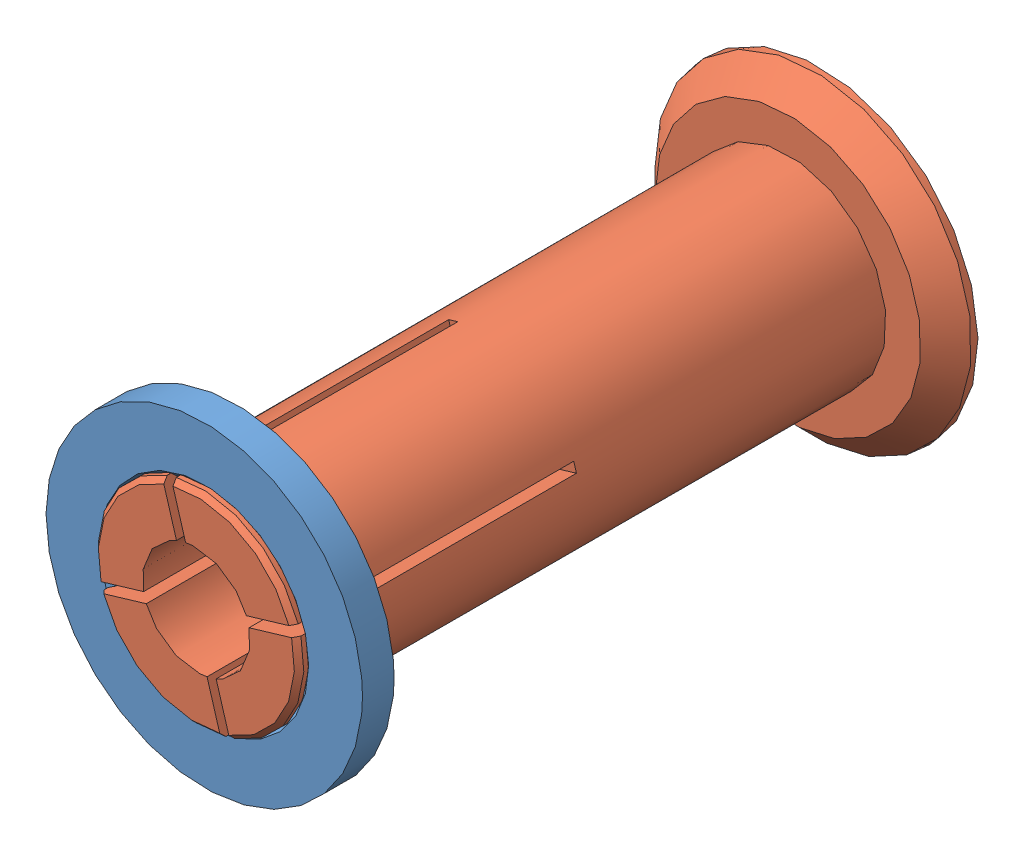
SolidWorks assembly 32-92-17-spool-adapter, configuration Default. Lengths in mm.
Overall size (62.18 62.18 98.5).
2 component instances, 2 part files, 2 mates.
Components (placement in the parent):
- 32-92-17-spool-adapter-female-1: 32-92-17-spool-adapter-female [Default] at (21.1752 30.9981 31.2213) size (50 50 5)
- 32-92-17-spool-adapter-male-1: 32-92-17-spool-adapter-male [Default] at (21.1752 30.9981 -56.0287) x (0.95852 0.285025 0) z (0 0 1) size (50 50 98.5)
Mates (geometry in assembly coordinates):
- Concentric1: concentric anti-aligned: cylinder of 32-92-17-spool-adapter-female-1 through (21.1752 30.9981 31.2213) axis (0 0 1) radius 15.75; cylinder of 32-92-17-spool-adapter-male-1 through (21.1752 30.9981 37.4713) axis (0 0 -1) radius 15.5
- Coincident1: coincident aligned: cone of 32-92-17-spool-adapter-female-1 through (21.1752 30.9981 36.2213) axis (0 0 -1); cone of 32-92-17-spool-adapter-male-1 through (21.1752 30.9981 35.9713) axis (0 0 -1)
